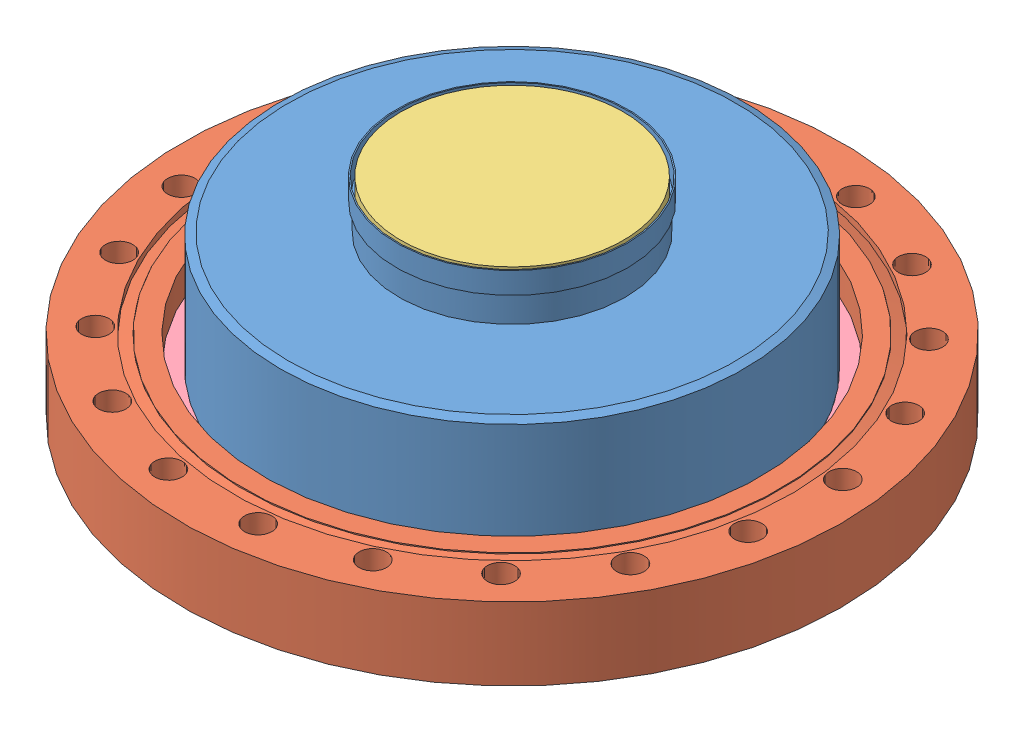
SolidWorks assembly Bucket Window, configuration Default. Lengths in mm.
Overall size (236 64.03 236).
4 component instances, 4 part files, 6 mates.
Components (placement in the parent):
- ISAdaptor-1: ISAdaptor [Default] at (127.1172 -28.8884 -80.9812) x (0.091876 0 -0.99577) z (-0.99577 0 -0.091876) size (142.24 51.09 142.24)
- ISFlange-1: ISFlange [Default] at (127.1172 -30.6577 -80.9812) x (-0.182612 0 0.983185) z (-0.983185 0 -0.182612) size (202.44 22.35 202.44)
- ISWindow-1: ISWindow [Default] at (127.1172 22.1997 -80.9812) size (68.33 6.35 68.33)
- RecessedRing-1: RecessedRing [Default] at (127.1172 -52.3227 -80.9812) size (152.4 1 152.4)
Mates (geometry in assembly coordinates):
- Concentric1: concentric anti-aligned: circle of ISAdaptor-1; circle of ISFlange-1
- Concentric2: concentric aligned: circle of ISFlange-1; circle of ISWindow-1
- Coincident1: coincident anti-aligned: plane of ISAdaptor-1 through (130.256 15.8497 -114.9997) normal (0 1 0); plane of ISWindow-1 through (127.1172 15.8497 -80.9812) normal (0 -1 0)
- Coincident2: coincident: plane of assembly; point of ISAdaptor-1; plane of ISFlange-1 through (113.2254 -41.8337 -6.1873) normal (0 -1 0)
- Concentric3: concentric aligned: circle of ISAdaptor-1; circle of RecessedRing-1
- Coincident4: coincident aligned: circle of ISAdaptor-1; circle of RecessedRing-1
